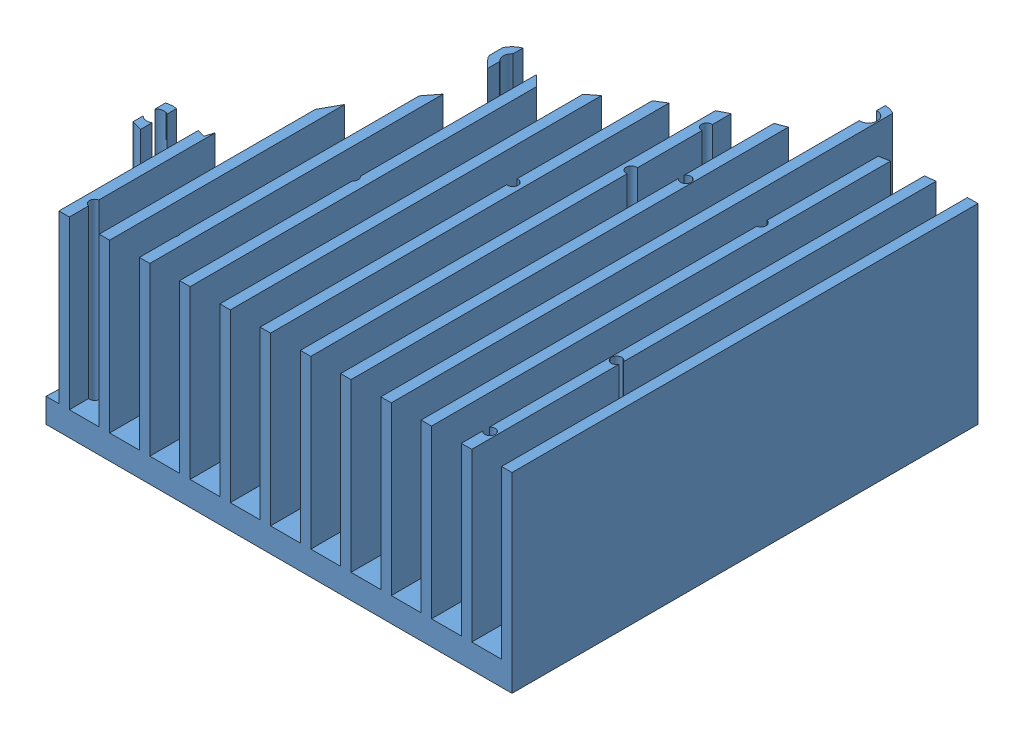
SolidWorks assembly Assem1, configuration Varsayılan. Lengths in mm.
Overall size (145.06 75 145.06).
3 component instances, 3 part files, 2 mates.
Components (placement in the parent):
- HeatSinkOneModule-1: HeatSinkOneModule [Varsayılan] at (-90.2788 -21.7775 -116.4111) size (145.06 55 145.06)
- paste2-3: paste2 [Varsayılan] at (14.8692 -21.7775 174.7131) x (0.939693 0 -0.34202) z (0 -1 0) size (49 15 10)
- metalresistor-1: metalresistor [Varsayılan] at (34.8297 -41.7775 173.6432) x (0.939693 0 -0.34202) z (0.34202 0 0.939693) size (49 10 15.71)
Mates (geometry in assembly coordinates):
- Coincident2: coincident anti-aligned: plane of HeatSinkOneModule-1 through (-90.2788 -21.7775 883.5889) normal (0 -1 0); plane of paste2-3 through (14.8692 -21.7775 174.7131) normal (0 1 0)
- Coincident3: coincident anti-aligned: plane of paste2-3 through (14.8692 -31.7775 174.7131) normal (0 -1 0); plane of metalresistor-1 through (34.8297 -31.7775 173.6432) normal (0 1 0)
